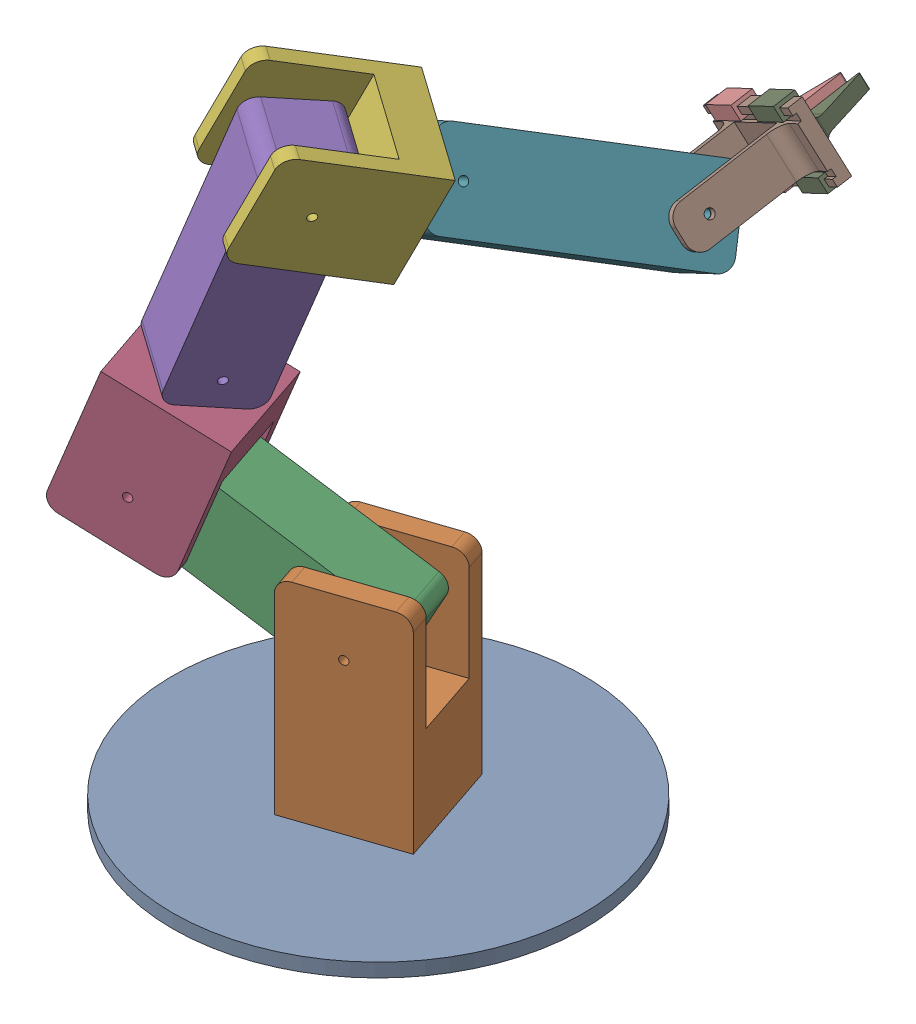
SolidWorks assembly .Prelim_arm_asm, configuration Default. Lengths in mm.
Overall size (327.73 453.04 452.24).
11 component instances, 6 part files, 18 mates.
Components (placement in the parent):
- Prelim_Base-1: Prelim_Base [Default] at (7.6614 10.7451 30.2462) size (300 10 300)
- Prelim_Link1-1: Prelim_Link1 [Default] at (7.6614 20.7451 30.2462) x (-0.319765 0 -0.947497) z (0.947497 0 -0.319765) size (80 150 80)
- Prelim_Link2-1: Prelim_Link2 [Default] at (19.5244 94.9215 52.628) x (-0.842815 0.456902 0.284437) z (-0.432913 -0.889517 0.146101) size (180 50 60)
- Prelim_Link3-1: Prelim_Link3 [Default] at (-137.7313 269.4596 37.0975) x (0.890621 -0.341251 -0.300571) z (-0.323335 -0.939972 0.10912) size (80 80 100)
- Prelim_Link2-2: Prelim_Link2 [Default] at (3.3995 411.681 30.8354) x (-0.323335 -0.939972 0.10912) z (0.462575 -0.2576 -0.848332) size (180 50 60)
- Prelim_Link3-3: Prelim_Link3 [Default] at (8.5636 338.1344 19.7871) x (0.367668 0.909749 -0.192816) z (-0.428184 0.349661 0.833304) size (80 80 100)
- Prelim_Link2-4: Prelim_Link2 [Default] at (36.0187 331.4244 -179.2974) x (-0.428184 0.349661 0.833304) z (-0.348714 0.786763 -0.509315) size (180 50 60)
- Claw_asm-1: Claw_asm [Default] at (19.7044 346.5646 -145.7812) x (0.833701 0.508666 0.214947) z (0.085468 0.265696 -0.960261) size (100 55 139.11)
  - Claw_track-1: Claw_track [Default] at (-26.3043 11.2167 54.6289) size (100 50 90)
  - claw_arm-1: claw_arm [Default] at (63.7933 53.7167 57.1289) x (0 0 1) z (-1 0 0) size (61.61 55 30.87)
  - claw_arm-2: claw_arm [Default] at (-16.3383 18.7167 57.1289) x (0 0 1) z (1 0 0) size (61.61 55 30.87)
Mates (geometry in assembly coordinates):
- Coincident1: coincident anti-aligned: plane of Prelim_Base-1 through (7.6614 20.7451 30.2462) normal (0 1 0); plane of Prelim_Link1-1 through (7.6614 20.7451 30.2462) normal (0 -1 0)
- Concentric1: concentric aligned: cylinder of Prelim_Base-1 through (7.6614 20.7451 30.2462) axis (0 -1 0) radius 3; cylinder of Prelim_Link1-1 through (7.6614 170.7451 30.2462) axis (0 -1 0) radius 3
- Concentric2: concentric anti-aligned: cylinder of Prelim_Link1-1 through (20.452 130.7451 68.1461) axis (-0.319765 0 -0.947497) radius 3; cylinder of Prelim_Link2-1 through (-0.3327 130.7451 6.5588) axis (0.319765 0 0.947497) radius 3
- Width1: width anti-aligned: plane of Prelim_Link2-1 through (19.5244 94.9215 52.628) normal (0.319765 0 0.947497); plane of Prelim_Link1-1 through (3.5362 94.9215 5.2531) normal (-0.319765 0 -0.947497); plane of Prelim_Link2-1 through (53.5554 90.7451 41.143) normal (-0.319765 0 -0.947497); plane of Prelim_Link1-1 through (37.5671 90.7451 -6.2318) normal (0.319765 0 0.947497)
- Concentric5: concentric anti-aligned: cylinder of Prelim_Link2-2 through (-86.0826 265.2092 61.8834) axis (-0.323335 -0.939972 0.10912) radius 3; cylinder of Prelim_Link3^.Prelim_arm_asm-2 through (-39.4456 154.4275 -51.9214) axis (-0.211367 -0.916055 0.340835) radius 3
- Coincident6: coincident anti-aligned: plane of Prelim_Link2-2 through (-96.0766 253.677 24.5721) normal (-0.323335 -0.939972 0.10912); plane of Prelim_Link3^.Prelim_arm_asm-2 through (-36.4163 112.7131 -44.7988) normal (-0.211367 -0.916055 0.340835)
- Concentric6: concentric aligned: cylinder of Prelim_Link3^.Prelim_arm_asm-2 through (-39.6638 141.4618 -57.5644) axis (-0.189548 0.38051 0.905143) radius 3; cylinder of Prelim_Link2-3 through (-48.3983 134.9862 -71.8426) axis (-0.315335 0.350646 0.881823) radius 3
- Width3: width aligned: plane of Prelim_Link2-3; plane of Prelim_Link3^.Prelim_arm_asm-2; plane of Prelim_Link2-3 through (-54.5883 140.0371 -41.3093) normal (0.189548 -0.38051 -0.905143); plane of Prelim_Link3^.Prelim_arm_asm-2 through (-32.7576 132.1757 -48.9) normal (-0.189548 0.38051 0.905143)
- Concentric7: concentric aligned: cylinder of Prelim_Link2-1 through (-118.3268 194.7113 46.38) axis (0.319765 0 0.947497) radius 3; cylinder of Prelim_Link3-1 through (-123.1233 194.7113 32.1675) axis (0.319765 0 0.947497) radius 3
- Width4: width anti-aligned: plane of Prelim_Link3-1 through (-144.2337 241.2604 49.8461) normal (0.319765 0 0.947497); plane of Prelim_Link2-1 through (-53.7982 213.9603 82.6502) normal (-0.319765 0 -0.947497); plane of Prelim_Link3-1 through (3.5362 94.9215 5.2531) normal (-0.319765 0 -0.947497); plane of Prelim_Link2-1 through (19.5244 94.9215 52.628) normal (0.319765 0 0.947497)
- Concentric8: concentric anti-aligned: cylinder of Prelim_Link3-1 through (-121.6494 161.8123 73.8866) axis (0.323335 0.939972 -0.10912) radius 3; cylinder of Prelim_Link2-2 through (-86.0826 265.2092 61.8834) axis (-0.323335 -0.939972 0.10912) radius 3
- Coincident7: coincident anti-aligned: plane of Prelim_Link3-1 through (-137.7313 269.4596 37.0975) normal (0.323335 0.939972 -0.10912); plane of Prelim_Link2-2 through (-96.0766 253.677 24.5721) normal (-0.323335 -0.939972 0.10912)
- Concentric9: concentric anti-aligned: cylinder of Prelim_Link2-2 through (-58.2203 411.8005 32.5628) axis (0.825517 -0.223819 0.518099) radius 3; cylinder of Prelim_Link3-3 through (-4.5617 397.2523 66.2392) axis (-0.825517 0.223819 -0.518099) radius 3
- Width5: width anti-aligned: plane of Prelim_Link3-3 through (-32.6548 437.0714 -6.9059) normal (0.825517 -0.223819 0.518099); plane of Prelim_Link2-2 through (-12.5371 350.8624 39.6052) normal (-0.825517 0.223819 -0.518099); plane of Prelim_Link3-3 through (-37.8764 422.8719 4.9305) normal (-0.825517 0.223819 -0.518099); plane of Prelim_Link2-2 through (3.3995 411.681 30.8354) normal (0.825517 -0.223819 0.518099)
- Concentric10: concentric anti-aligned: cylinder of Prelim_Link3-3 through (-52.5688 418.4432 74.6809) axis (0.428184 -0.349661 -0.833304) radius 3; cylinder of Prelim_Link2-4 through (-5.4686 379.9805 -16.9825) axis (-0.428184 0.349661 0.833304) radius 3
- Coincident8: coincident anti-aligned: plane of Prelim_Link3-3 through (8.5636 338.1344 19.7871) normal (0.428184 -0.349661 -0.833304); plane of Prelim_Link2-4 through (0.6307 419.7966 -18.5552) normal (-0.428184 0.349661 0.833304)
- Concentric11: concentric anti-aligned: cylinder of Prelim_Link2-4 through (79.6015 340.248 -136.6045) axis (-0.833701 -0.508666 -0.214947) radius 3; cylinder of Claw_asm-1/Claw_track-1 through (17.0739 302.098 -152.7255) axis (0.833701 0.508666 0.214947) radius 3.1732
- Width6: width anti-aligned: plane of Claw_asm-1/Claw_track-1 through (69.7087 347.2182 -114.7287) normal (-0.833701 -0.508666 -0.214947); plane of Prelim_Link2-4 through (28.0237 321.7849 -125.4761) normal (0.833701 0.508666 0.214947); plane of Claw_asm-1/Claw_track-1 through (77.7037 356.8576 -168.55) normal (0.833701 0.508666 0.214947); plane of Prelim_Link2-4 through (36.0187 331.4244 -179.2974) normal (-0.833701 -0.508666 -0.214947)
